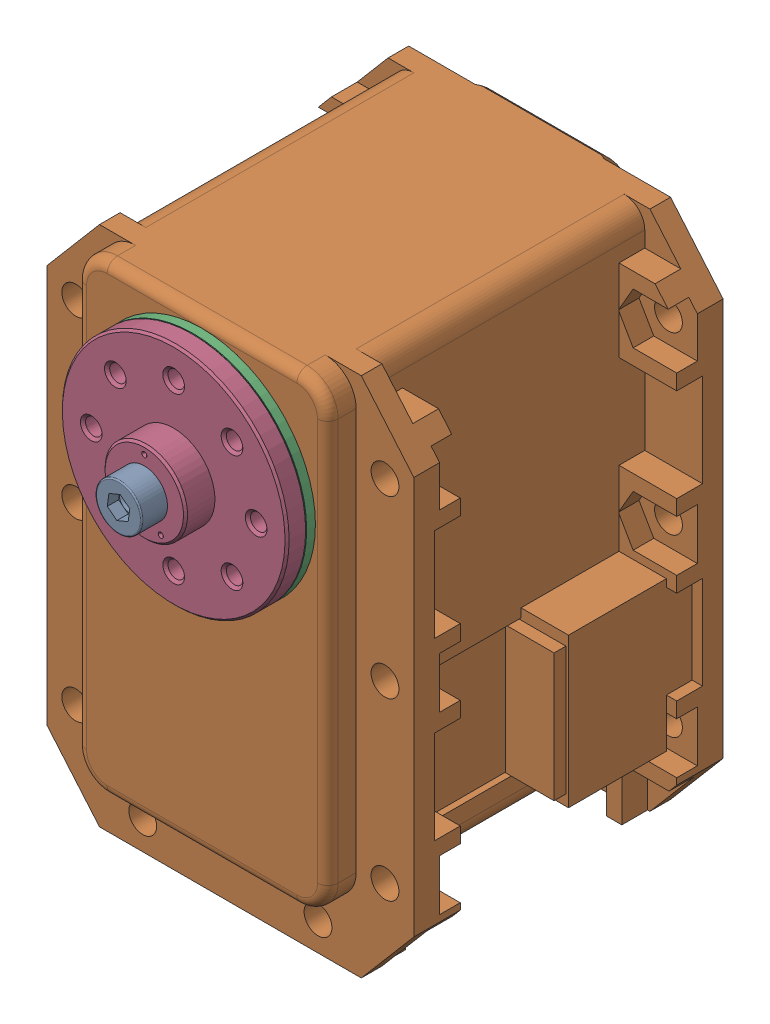
SolidWorks assembly MX-28(T)-5, configuration Default. Lengths in mm.
Overall size (35.6 54.13 45.1).
4 component instances, 4 part files, 0 mates.
Components (placement in the parent):
- WB_M2.5x8-1: WB_M2.5x8 [Default] at (0 0 25.85) x (0 0 -1) z (-0.991137 0.132843 0) size (10.5 4.5 4.5)
- dynamixel_x28series(Défaut)-1: dynamixel_x28series(Défaut) [Default] at origin size (35.6 50.71 41.85)
- trust_washer(Défaut)-1: trust_washer(Défaut) [Default] at (0 0 18.6) x (-0.666375 -0.745617 0) z (0.745617 -0.666375 0) size (22 0.85 22)
- HN07-N101(Défaut)-1: HN07-N101(Défaut) [Default] at (0 0 18.5) x (1 0 0) z (0 -1 0) size (22 5.85 22)
